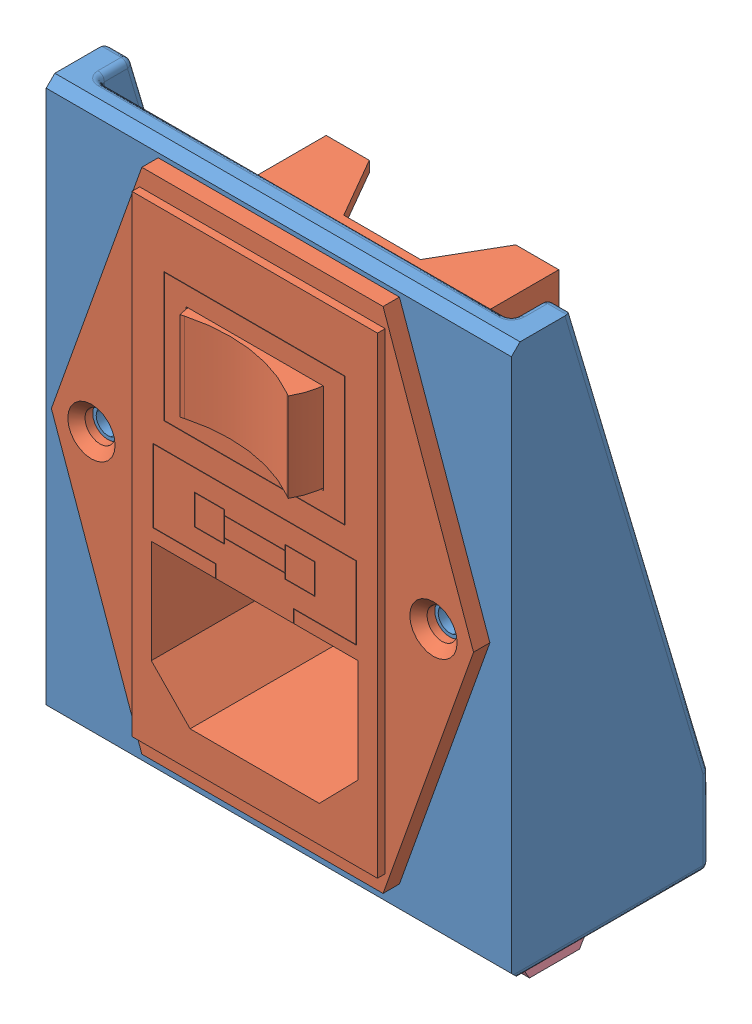
SolidWorks assembly Outlet_Switch, configuration Default. Lengths in mm.
Overall size (54 69.5 28.75).
6 component instances, 4 part files, 13 mates.
Components (placement in the parent):
- Outlet_Switch_Mount-1: Outlet_Switch_Mount [Default] at (-1.4505 -29.115 8.6642) size (54 64 23)
- Amazon_Electrical_Fused_Plug-1: Amazon_Electrical_Fused_Plug [Default] at (-1.4505 3.885 11.6642) x (-1 0 0) z (0 0 1) size (49 59 24.75)
- 5mmX10mm_Buttonhead(McMaster_91239A224)-1: 5mmX10mm_Buttonhead(McMaster_91239A224) [91239A224] at (15.5495 -21.365 1.6642) x (0.942594 0 0.33394) z (0 1 0) size (9.5 9.5 13.21)
- 5mmX10mm_Buttonhead(McMaster_91239A224)-2: 5mmX10mm_Buttonhead(McMaster_91239A224) [91239A224] at (-18.4505 -21.365 1.6642) x (1 0 0) z (0 1 0) size (9.5 9.5 13.21)
- HNTTSN5-5-1: HNTTSN5-5 [Default] at (15.5495 -30.315 1.6642) x (0 1 0) z (-1 0 0) size (4.3 10 10)
- HNTTSN5-5-2: HNTTSN5-5 [Default] at (-18.4505 -30.315 1.6642) x (0 1 0) z (-1 0 0) size (4.3 10 10)
Mates (geometry in assembly coordinates):
- Coincident2: coincident anti-aligned: plane of Outlet_Switch_Mount-1 through (-1.4505 -29.115 11.6642) normal (0 0 1); plane of Amazon_Electrical_Fused_Plug-1 through (-1.4505 3.885 11.6642) normal (0 0 -1)
- Coincident5: coincident anti-aligned: plane of Outlet_Switch_Mount-1 through (-1.4505 -29.115 8.6642) normal (1 0 0); plane of Amazon_Electrical_Fused_Plug-1
- Concentric1: concentric aligned: cylinder of Outlet_Switch_Mount-1 through (-21.3005 3.885 11.6642) axis (0 0 -1) radius 1.35; cylinder of Amazon_Electrical_Fused_Plug-1 through (-21.3005 3.885 13.5642) axis (0 0 -1) radius 1.75
- Concentric2: concentric anti-aligned: cylinder of Outlet_Switch_Mount-1 through (15.5495 -24.115 1.6642) axis (0 -1 0) radius 2.6; cylinder of 5mmX10mm_Buttonhead(McMaster_91239A224)-1 through (15.5495 -21.365 1.6642) axis (0 1 0) radius 4.75
- Concentric3: concentric anti-aligned: cylinder of Outlet_Switch_Mount-1 through (-18.4505 -24.115 1.6642) axis (0 -1 0) radius 2.6; cylinder of 5mmX10mm_Buttonhead(McMaster_91239A224)-2 through (-18.4505 -21.365 1.6642) axis (0 1 0) radius 4.75
- Coincident6: coincident anti-aligned: plane of Outlet_Switch_Mount-1 through (-1.4505 -24.115 8.6642) normal (0 1 0); plane of 5mmX10mm_Buttonhead(McMaster_91239A224)-2 through (-18.4505 -24.115 6.4142) normal (0 -1 0)
- Coincident7: coincident anti-aligned: plane of Outlet_Switch_Mount-1 through (-1.4505 -24.115 8.6642) normal (0 1 0); plane of 5mmX10mm_Buttonhead(McMaster_91239A224)-1 through (13.9632 -24.115 6.1415) normal (0 -1 0)
- Concentric4: concentric anti-aligned: cylinder of 5mmX10mm_Buttonhead(McMaster_91239A224)-2 through (-18.4505 -21.365 1.6642) axis (0 1 0) radius 4.75; cylinder of HNTTSN5-5-2 through (-18.4505 -30.315 1.6642) axis (0 -1 0) radius 2.067
- Concentric5: concentric anti-aligned: cylinder of 5mmX10mm_Buttonhead(McMaster_91239A224)-1 through (15.5495 -21.365 1.6642) axis (0 1 0) radius 4.75; cylinder of HNTTSN5-5-1 through (15.5495 -30.315 1.6642) axis (0 -1 0) radius 2.067
- Distance1: distance = 2 mm anti-aligned: plane of HNTTSN5-5-1 through (10.5495 -31.115 6.6642) normal (0 1 0); plane of Outlet_Switch_Mount-1 through (-28.4505 -29.115 11.6642) normal (0 -1 0)
- Distance2: distance = 2 mm anti-aligned: plane of Outlet_Switch_Mount-1 through (-28.4505 -29.115 11.6642) normal (0 -1 0); plane of HNTTSN5-5-2 through (-23.4505 -31.115 -1.2358) normal (0 1 0)
- Parallel2: parallel aligned: plane of Outlet_Switch_Mount-1 through (-28.4505 34.885 11.6642) normal (-1 0 0); plane of HNTTSN5-5-2 through (-23.4505 -30.315 1.6642) normal (-1 0 0)
- Parallel3: parallel anti-aligned: plane of Outlet_Switch_Mount-1 through (-28.4505 34.885 11.6642) normal (-1 0 0); plane of HNTTSN5-5-1 through (20.5495 -30.315 1.6642) normal (1 0 0)
